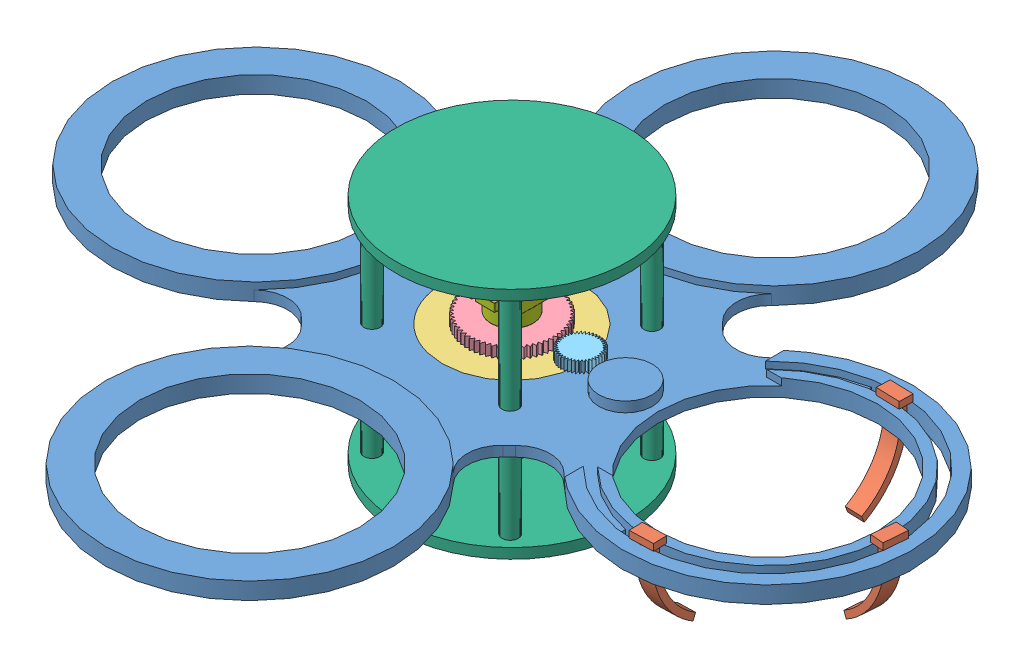
SolidWorks assembly bırakma mekanizması, configuration Varsayılan. Lengths in mm.
Overall size (237.92 69 237.92).
11 component instances, 7 part files, 23 mates.
Components (placement in the parent):
- sepet-1: sepet [Varsayılan] at (-29.8137 -11.9862 237.9187) size (237.92 6 237.92)
- tutucu-1: tutucu [Varsayılan] at (84.0121 -6.9862 242.0738) x (0.084339 0 -0.996437) z (0.996437 0 0.084339) size (7 27 13.83)
- dişli taşıyıcı-1: dişli taşıyıcı [Varsayılan] at (-29.8137 -11.9862 237.9187) x (0.997862 0 -0.065353) z (0.065353 0 0.997862) size (41 6 41)
- büyük dişli-1: büyük dişli [Varsayılan] at (-29.8137 -5.9862 237.9187) x (0.867707 0 0.497075) z (0.497075 0 -0.867707) size (26.15 3 26.15)
- küçük dişli-1: küçük dişli [Varsayılan] at (-10.8543 -5.9862 236.677) x (-0.998655 0 0.051849) z (0.051849 0 0.998655) size (11.31 3 11.31)
- servo tutucu-1: servo tutucu [Varsayılan] at (-29.8137 21.0138 237.9187) x (0.716227 0 -0.697867) z (0.697867 0 0.716227) size (68.45 33 68.45)
- TP SG90-1: TP SG90 [Varsayılan] at (-29.7682 20.8138 232.6689) x (-0.999962 0 -0.008668) z (-0.008668 0 0.999962) size (12.64 29.82 33.01)
- TP SG90-2: TP SG90 [Varsayılan] at (-29.7044 -38.7862 232.6698) x (0.999783 0 0.02081) z (-0.02081 0 0.999783) size (12.64 29.82 33.01)
- servo tutucu-2: servo tutucu [Varsayılan] at (-29.8137 -41.9862 237.9187) x (-0.697867 0 -0.716227) z (-0.716227 0 0.697867) size (68.45 33 68.45)
- tutucu-2: tutucu [Varsayılan] at (50.2676 -6.9862 201.5912) x (-0.999549 0 -0.030018) z (0.030018 0 -0.999549) size (7 27 13.83)
- tutucu-3: tutucu [Varsayılan] at (45.2368 -6.9862 276.3799) x (0.999575 0 -0.029138) z (0.029138 0 0.999575) size (7 27 13.83)
Mates (geometry in assembly coordinates):
- Çakışık1: coincident anti-aligned: plane of sepet-1 through (46.6457 -6.9862 238.9111) normal (0 1 0); plane of tutucu-1 through (84.0121 -6.9862 242.0738) normal (0 -1 0)
- YolMontajİlişkisi1: path = 30 mm: point of tutucu-1; circle of sepet-1
- Eş Merkezli4: concentric anti-aligned: cylinder of sepet-1 through (-29.8137 -11.9862 237.9187) axis (0 1 0) radius 20.5; cylinder of dişli taşıyıcı-1 through (-29.8137 -8.9862 237.9187) axis (0 -1 0) radius 20.5
- Çakışık4: coincident anti-aligned: plane of dişli taşıyıcı-1 through (-29.8137 -8.9862 237.9187) normal (0 1 0); plane of büyük dişli-1 through (-29.8137 -8.9862 237.9187) normal (0 -1 0)
- Eş Merkezli6: concentric aligned: cylinder of sepet-1 through (-29.8137 -11.9862 237.9187) axis (0 1 0) radius 20.5; cylinder of büyük dişli-1 through (-29.8137 -8.9862 237.9187) axis (0 1 0) radius 13.08
- Çakışık5: coincident aligned: plane of sepet-1 through (-29.8137 -8.9862 237.9187) normal (0 1 0); plane of dişli taşıyıcı-1 through (-29.8137 -8.9862 237.9187) normal (0 1 0)
- Eş Merkezli7: concentric anti-aligned: cylinder of dişli taşıyıcı-1 through (-10.8543 -5.9862 236.677) axis (0 -1 0) radius 1; cylinder of küçük dişli-1 through (-10.8543 -8.9862 236.677) axis (0 1 0) radius 5.6694
- Çakışık6: coincident anti-aligned: plane of sepet-1 through (-29.8137 -8.9862 237.9187) normal (0 1 0); plane of küçük dişli-1 through (-10.8543 -8.9862 236.677) normal (0 -1 0)
- Çakışık7: coincident anti-aligned: plane of sepet-1 through (-29.8137 -8.9862 237.9187) normal (0 1 0); plane of servo tutucu-1 through (-29.8137 -8.9862 237.9187) normal (0 -1 0)
- Eş Merkezli8: concentric aligned: cylinder of sepet-1 through (-29.8137 -8.9862 237.9187) axis (0 -1 0) radius 43.9658; cylinder of servo tutucu-1 through (-29.8137 24.0138 237.9187) axis (0 -1 0) radius 34.2244
- Çakışık8: coincident anti-aligned: plane of sepet-1 through (-29.8137 -8.9862 237.9187) normal (0 1 0); plane of TP SG90-1 through (-29.8137 -8.9862 237.9187) normal (0 -1 0)
- Eş Merkezli9: concentric: cylinder of assembly; cylinder of büyük dişli-1 through (-29.8137 -8.9862 237.9187) axis (0 1 0) radius 13.08; cylinder of TP SG90-1 through (-29.8137 -1.6862 237.9187) axis (0 -1 0) radius 6.25
- Çakışık9: coincident aligned: plane of dişli taşıyıcı-1 through (-29.8137 -8.9862 237.9187) normal (0 1 0); plane of TP SG90-2 through (-29.8137 -8.9862 237.9187) normal (0 1 0)
- Eş Merkezli10: concentric anti-aligned: cylinder of dişli taşıyıcı-1 through (-29.8137 -8.9862 237.9187) axis (0 -1 0) radius 20.5; cylinder of TP SG90-2 through (-29.8137 -16.2862 237.9187) axis (0 1 0) radius 6.25
- Çakışık10: coincident anti-aligned: plane of sepet-1 through (-29.8137 -11.9862 237.9187) normal (0 -1 0); plane of servo tutucu-2 through (-29.8137 -11.9862 237.9187) normal (0 1 0)
- Eş Merkezli11: concentric anti-aligned: cylinder of sepet-1 through (-29.8137 -8.9862 237.9187) axis (0 -1 0) radius 43.9658; cylinder of servo tutucu-2 through (-29.8137 -44.9862 237.9187) axis (0 1 0) radius 34.2244
- Eş Merkezli12: concentric anti-aligned: cylinder of servo tutucu-1 through (-50.2084 -8.9862 216.9874) axis (0 1 0) radius 2.3965; cylinder of servo tutucu-2 through (-50.2084 -11.9862 216.9874) axis (0 -1 0) radius 2.3965
- Çakışık11: coincident anti-aligned: plane of sepet-1 through (46.6457 -6.9862 238.9111) normal (0 1 0); plane of tutucu-2 through (50.2676 -6.9862 201.5912) normal (0 -1 0)
- Çakışık12: coincident anti-aligned: plane of sepet-1 through (46.6457 -6.9862 238.9111) normal (0 1 0); plane of tutucu-3 through (45.2368 -6.9862 276.3799) normal (0 -1 0)
- YolMontajİlişkisi2: path: circle of sepet-1
- YolMontajİlişkisi3: path: circle of sepet-1
- YolMontajİlişkisi4: path: point of tutucu-3; circle of sepet-1
- YolMontajİlişkisi5: path: circle of sepet-1
